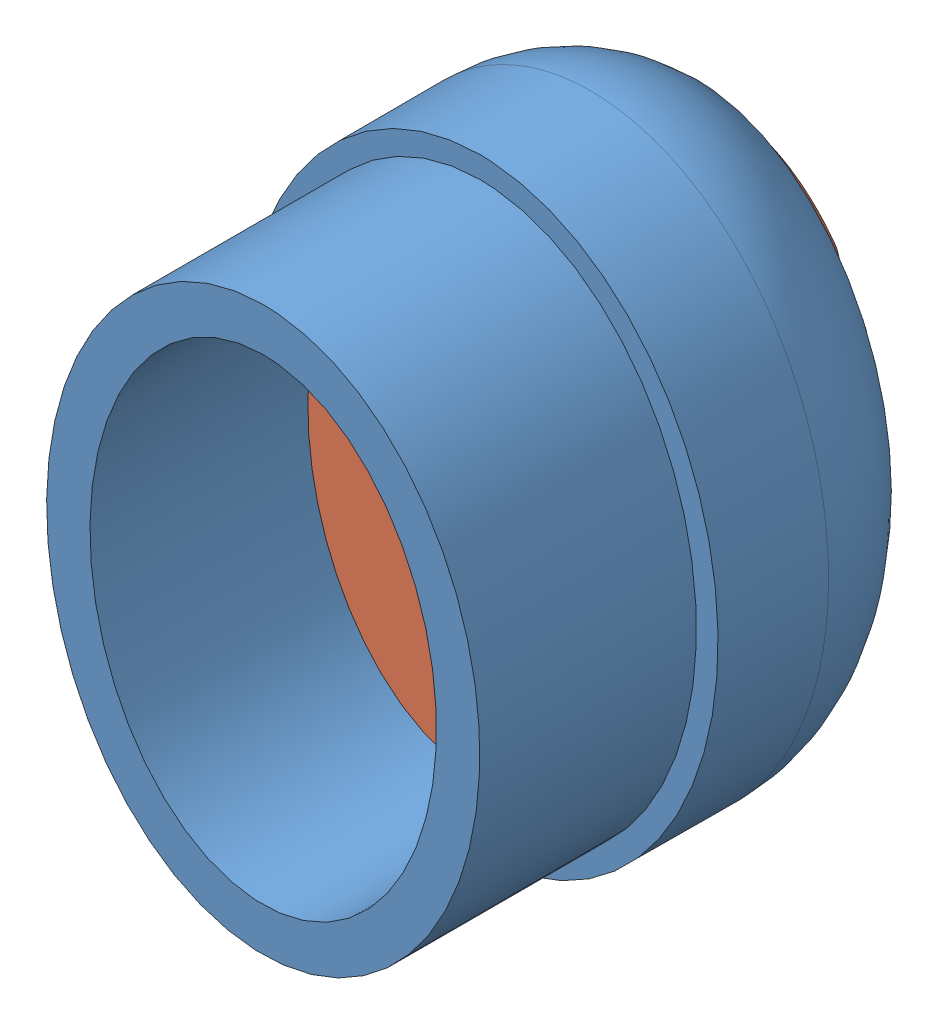
SolidWorks assembly ojo der, configuration Predeterminado. Lengths in mm.
Overall size (24.18 30.22 22.23).
2 component instances, 2 part files, 2 mates.
Components (placement in the parent):
- ojo-1: ojo [Predeterminado] at (-0.1179 1.8575 28) size (24.18 30.22 20)
- pupila-1: pupila [Predeterminado] at (-0.0568 1.813 38) x (-1 0 0) z (0 0 -1) size (18 24 12.23)
Mates (geometry in assembly coordinates):
- Coincidente1: coincident anti-aligned: plane of ojo-1 through (-0.1179 1.8575 30) normal (0 0 -1); plane of ? through (-0.1344 1.8621 30) normal (0 0 1)
- Coincidente2: coincident anti-aligned: plane of ojo-1 through (-0.1179 1.8575 30) normal (0 0 -1); plane of pupila-1 through (-0.0568 1.813 30) normal (0 0 1)
